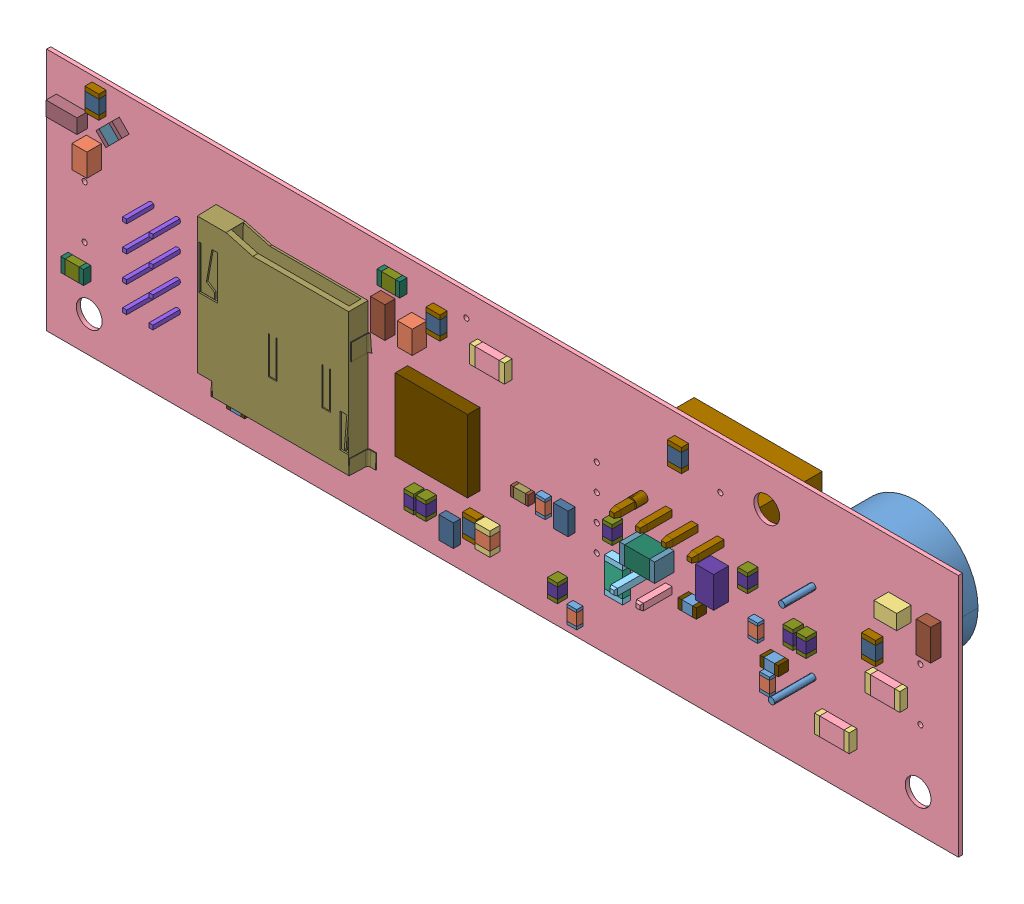
SolidWorks assembly PCB, configuration Default. Lengths in mm.
Overall size (88.26 23.62 14).
270 component instances, 41 part files, 0 mates.
Components (placement in the parent):
- R05-2-1: R05-2 [Default] at origin size (0.95 1.7 0.6)
  - 959206216-2-1: 959206216-2 [Default] at (123.9521 73.9609 0) size (0.95 0.27 0.6)
    - Extruded-62-1: Extruded-62 [Default] at origin size (0.95 0.27 0.6)
  - 959206352-2-1: 959206352-2 [Default] at (123.9521 74.6759 0) size (0.95 1.16 0.6)
    - Extruded-63-1: Extruded-63 [Default] at origin size (0.95 1.16 0.6)
  - 959206216-2-2: 959206216-2 [Default] at (123.9521 75.3909 0) size (0.95 0.27 0.6)
    - Extruded-62-1: Extruded-62 [Default] at origin size (0.95 0.27 0.6)
- R04-2-1: R04-2 [Default] at origin size (0.95 1.7 0.6)
  - 959206216-2-1: 959206216-2 [Default] at (141.478 81.581 0) size (0.95 0.27 0.6)
    - Extruded-62-1: Extruded-62 [Default] at origin size (0.95 0.27 0.6)
  - 959206352-2-1: 959206352-2 [Default] at (141.478 82.296 0) size (0.95 1.16 0.6)
    - Extruded-63-1: Extruded-63 [Default] at origin size (0.95 1.16 0.6)
  - 959206216-2-2: 959206216-2 [Default] at (141.478 83.011 0) size (0.95 0.27 0.6)
    - Extruded-62-1: Extruded-62 [Default] at origin size (0.95 0.27 0.6)
- R03-2-1: R03-2 [Default] at origin size (3.35 1.75 0.75)
  - 959206760-2-1: 959206760-2 [Default] at (147.8506 77.6516 0) size (0.49 1.75 0.75)
    - Extruded-64-1: Extruded-64 [Default] at origin size (0.49 1.75 0.75)
  - 959206896-2-1: 959206896-2 [Default] at (149.2781 77.6516 0) size (2.36 1.75 0.75)
    - Extruded-65-1: Extruded-65 [Default] at origin size (2.36 1.75 0.75)
  - 959206760-2-2: 959206760-2 [Default] at (150.7056 77.6516 0) size (0.49 1.75 0.75)
    - Extruded-64-1: Extruded-64 [Default] at origin size (0.49 1.75 0.75)
- R02-2-1: R02-2 [Default] at origin size (1.75 3.35 0.75)
  - 959207032-2-1: 959207032-2 [Default] at (128.1431 81.3844 0) size (1.75 0.49 0.75)
    - Extruded-66-1: Extruded-66 [Default] at origin size (1.75 0.49 0.75)
  - 959207168-2-1: 959207168-2 [Default] at (128.1431 79.9569 0) size (1.75 2.36 0.75)
    - Extruded-67-1: Extruded-67 [Default] at origin size (1.75 2.36 0.75)
  - 959207032-2-2: 959207032-2 [Default] at (128.1431 78.5294 0) size (1.75 0.49 0.75)
    - Extruded-66-1: Extruded-66 [Default] at origin size (1.75 0.49 0.75)
- R01-2-1: R01-2 [Default] at origin size (3.35 1.75 0.75)
  - 959206760-2-1: 959206760-2 [Default] at (117.3285 91.9479 0) size (0.49 1.75 0.75)
    - Extruded-64-1: Extruded-64 [Default] at origin size (0.49 1.75 0.75)
  - 959206896-2-1: 959206896-2 [Default] at (115.901 91.9479 0) size (2.36 1.75 0.75)
    - Extruded-65-1: Extruded-65 [Default] at origin size (2.36 1.75 0.75)
  - 959206760-2-2: 959206760-2 [Default] at (114.4735 91.9479 0) size (0.49 1.75 0.75)
    - Extruded-64-1: Extruded-64 [Default] at origin size (0.49 1.75 0.75)
- U3-2-1: U3-2 [Default] at origin size (43.25 15.95 5.5)
  - 959206080-2-1: 959206080-2 [Default] at (102.177 84.441 -2.3912) size (43.25 15.95 2)
    - Extruded-68-1: Extruded-68 [Default] at origin size (43.25 15.95 2)
  - 959205944-2-1: 959205944-2 [Default] at (85.217 88.291 -2.8912) size (0.4 0.4 5.5)
    - Extruded-69-1: Extruded-69 [Default] at origin size (0.4 0.4 5.5)
  - 959205944-2-2: 959205944-2 [Default] at (85.217 85.751 -2.8912) size (0.4 0.4 5.5)
    - Extruded-69-1: Extruded-69 [Default] at origin size (0.4 0.4 5.5)
  - 959205944-2-3: 959205944-2 [Default] at (82.677 88.291 -2.8912) size (0.4 0.4 5.5)
    - Extruded-69-1: Extruded-69 [Default] at origin size (0.4 0.4 5.5)
  - 959205944-2-4: 959205944-2 [Default] at (82.677 85.751 -2.8912) size (0.4 0.4 5.5)
    - Extruded-69-1: Extruded-69 [Default] at origin size (0.4 0.4 5.5)
  - 959205944-2-5: 959205944-2 [Default] at (85.217 83.211 -2.8912) size (0.4 0.4 5.5)
    - Extruded-69-1: Extruded-69 [Default] at origin size (0.4 0.4 5.5)
  - 959205944-2-6: 959205944-2 [Default] at (85.217 80.671 -2.8912) size (0.4 0.4 5.5)
    - Extruded-69-1: Extruded-69 [Default] at origin size (0.4 0.4 5.5)
  - 959205944-2-7: 959205944-2 [Default] at (82.677 83.211 -2.8912) size (0.4 0.4 5.5)
    - Extruded-69-1: Extruded-69 [Default] at origin size (0.4 0.4 5.5)
  - 959205944-2-8: 959205944-2 [Default] at (82.677 80.671 -2.8912) size (0.4 0.4 5.5)
    - Extruded-69-1: Extruded-69 [Default] at origin size (0.4 0.4 5.5)
- R11-2-1: R11-2 [Default] at origin size (1.35 2.2 0.7)
  - 959207304-2-1: 959207304-2 [Default] at (133.9849 94.0691 0) size (1.35 0.42 0.7)
    - Extruded-70-1: Extruded-70 [Default] at origin size (1.35 0.42 0.7)
  - 959207440-2-1: 959207440-2 [Default] at (133.9849 93.1791 0) size (1.35 1.36 0.7)
    - Extruded-71-1: Extruded-71 [Default] at origin size (1.35 1.36 0.7)
  - 959207304-2-2: 959207304-2 [Default] at (133.9849 92.2891 0) size (1.35 0.42 0.7)
    - Extruded-70-1: Extruded-70 [Default] at origin size (1.35 0.42 0.7)
- Q3-2-1: Q3-2 [Default] at origin size (1.4 3 1)
  - 959206624-2-1: 959206624-2 [Default] at (105.664 90.805 0.1) size (1.4 3 1)
    - Extruded-72-1: Extruded-72 [Default] at origin size (1.4 3 1)
- P6-2-1: P6-2 [Default] at origin size (16.31 15.21 2.47)
  - User Library-Micro SD-2-1: User Library-Micro SD-2 [Default] at (103.6713 76.9862 0.04) x (-1 0 0) z (0 0 1) size (16.31 15.21 2.47)
- Q1-2-1: Q1-2 [Default] at origin size (3 1.4 1)
  - 959206488-2-1: 959206488-2 [Default] at (75.057 92.3634 0.1) size (3 1.4 1)
    - Extruded-73-1: Extruded-73 [Default] at origin size (3 1.4 1)
- C1-2-1: C1-2 [Default] at origin size (3.4 1.8 1.9)
  - 959208392-2-1: 959208392-2 [Default] at (133.022 83.687 0) size (0.5 1.8 1.9)
    - Extruded-74-1: Extruded-74 [Default] at origin size (0.5 1.8 1.9)
  - 959208392-2-2: 959208392-2 [Default] at (130.122 83.687 0) size (0.5 1.8 1.9)
    - Extruded-74-1: Extruded-74 [Default] at origin size (0.5 1.8 1.9)
  - 959208256-2-1: 959208256-2 [Default] at (131.572 83.687 0) size (2.4 1.8 1.9)
    - Extruded-75-1: Extruded-75 [Default] at origin size (2.4 1.8 1.9)
- C2-2-1: C2-2 [Default] at origin size (0.95 1.75 1)
  - 959208664-2-1: 959208664-2 [Default] at (140.8925 85.698 0) size (0.95 0.35 1)
    - Extruded-76-1: Extruded-76 [Default] at origin size (0.95 0.35 1)
  - 959208664-2-2: 959208664-2 [Default] at (140.8925 87.098 0) size (0.95 0.35 1)
    - Extruded-76-1: Extruded-76 [Default] at origin size (0.95 0.35 1)
  - 959208528-2-1: 959208528-2 [Default] at (140.8925 86.398 0) size (0.95 1.05 1)
    - Extruded-77-1: Extruded-77 [Default] at origin size (0.95 1.05 1)
- C3-2-1: C3-2 [Default] at origin size (0.95 1.75 1)
  - 959208664-2-1: 959208664-2 [Default] at (146.558 83.0961 0) size (0.95 0.35 1)
    - Extruded-76-1: Extruded-76 [Default] at origin size (0.95 0.35 1)
  - 959208664-2-2: 959208664-2 [Default] at (146.558 84.4961 0) size (0.95 0.35 1)
    - Extruded-76-1: Extruded-76 [Default] at origin size (0.95 0.35 1)
  - 959208528-2-1: 959208528-2 [Default] at (146.558 83.7961 0) size (0.95 1.05 1)
    - Extruded-77-1: Extruded-77 [Default] at origin size (0.95 1.05 1)
- C5-2-1: C5-2 [Default] at origin size (1.75 0.95 1)
  - 959208936-2-1: 959208936-2 [Default] at (142.772 80.518 0) size (0.35 0.95 1)
    - Extruded-78-1: Extruded-78 [Default] at origin size (0.35 0.95 1)
  - 959208936-2-2: 959208936-2 [Default] at (144.172 80.518 0) size (0.35 0.95 1)
    - Extruded-78-1: Extruded-78 [Default] at origin size (0.35 0.95 1)
  - 959208800-2-1: 959208800-2 [Default] at (143.472 80.518 0) size (1.05 0.95 1)
    - Extruded-79-1: Extruded-79 [Default] at origin size (1.05 0.95 1)
- C6-2-1: C6-2 [Default] at origin size (1.75 0.95 1)
  - 959208800-2-1: 959208800-2 [Default] at (135.5285 81.379 0) size (1.05 0.95 1)
    - Extruded-79-1: Extruded-79 [Default] at origin size (1.05 0.95 1)
  - 959208936-2-1: 959208936-2 [Default] at (136.2285 81.379 0) size (0.35 0.95 1)
    - Extruded-78-1: Extruded-78 [Default] at origin size (0.35 0.95 1)
  - 959208936-2-2: 959208936-2 [Default] at (134.8286 81.379 0) size (0.35 0.95 1)
    - Extruded-78-1: Extruded-78 [Default] at origin size (0.35 0.95 1)
- C7-2-1: C7-2 [Default] at origin size (0.95 1.75 1)
  - 959208528-2-1: 959208528-2 [Default] at (145.288 83.8282 0) size (0.95 1.05 1)
    - Extruded-77-1: Extruded-77 [Default] at origin size (0.95 1.05 1)
  - 959208664-2-1: 959208664-2 [Default] at (145.288 83.1282 0) size (0.95 0.35 1)
    - Extruded-76-1: Extruded-76 [Default] at origin size (0.95 0.35 1)
  - 959208664-2-2: 959208664-2 [Default] at (145.288 84.5282 0) size (0.95 0.35 1)
    - Extruded-76-1: Extruded-76 [Default] at origin size (0.95 0.35 1)
- C8-2-1: C8-2 [Default] at origin size (1.45 2.2 1)
  - 959207984-2-1: 959207984-2 [Default] at (115.697 77.2073 0) size (1.45 1.2 1)
    - Extruded-80-1: Extruded-80 [Default] at origin size (1.45 1.2 1)
  - 959207848-2-1: 959207848-2 [Default] at (115.697 78.0573 0) size (1.45 0.5 1)
    - Extruded-81-1: Extruded-81 [Default] at origin size (1.45 0.5 1)
  - 959207848-2-2: 959207848-2 [Default] at (115.697 76.3573 0) size (1.45 0.5 1)
    - Extruded-81-1: Extruded-81 [Default] at origin size (1.45 0.5 1)
- C9-2-1: C9-2 [Default] at origin size (0.95 1.75 1)
  - 959208528-2-1: 959208528-2 [Default] at (108.577 76.835 0) size (0.95 1.05 1)
    - Extruded-77-1: Extruded-77 [Default] at origin size (0.95 1.05 1)
  - 959208664-2-1: 959208664-2 [Default] at (108.577 76.135 0) size (0.95 0.35 1)
    - Extruded-76-1: Extruded-76 [Default] at origin size (0.95 0.35 1)
  - 959208664-2-2: 959208664-2 [Default] at (108.577 77.535 0) size (0.95 0.35 1)
    - Extruded-76-1: Extruded-76 [Default] at origin size (0.95 0.35 1)
- C10-2-1: C10-2 [Default] at origin size (0.95 1.75 1)
  - 959208664-2-1: 959208664-2 [Default] at (109.7632 77.5843 0) size (0.95 0.35 1)
    - Extruded-76-1: Extruded-76 [Default] at origin size (0.95 0.35 1)
  - 959208664-2-2: 959208664-2 [Default] at (109.7632 76.1843 0) size (0.95 0.35 1)
    - Extruded-76-1: Extruded-76 [Default] at origin size (0.95 0.35 1)
  - 959208528-2-1: 959208528-2 [Default] at (109.7632 76.8843 0) size (0.95 1.05 1)
    - Extruded-77-1: Extruded-77 [Default] at origin size (0.95 1.05 1)
- C11-2-1: C11-2 [Default] at origin size (0.95 1.75 1)
  - 959208664-2-1: 959208664-2 [Default] at (122.4827 75.652 0) size (0.95 0.35 1)
    - Extruded-76-1: Extruded-76 [Default] at origin size (0.95 0.35 1)
  - 959208664-2-2: 959208664-2 [Default] at (122.4827 77.052 0) size (0.95 0.35 1)
    - Extruded-76-1: Extruded-76 [Default] at origin size (0.95 0.35 1)
  - 959208528-2-1: 959208528-2 [Default] at (122.4827 76.352 0) size (0.95 1.05 1)
    - Extruded-77-1: Extruded-77 [Default] at origin size (0.95 1.05 1)
- C12-2-1: C12-2 [Default] at origin size (1.75 0.95 1)
  - 959208936-2-1: 959208936-2 [Default] at (92.521 76.327 0) size (0.35 0.95 1)
    - Extruded-78-1: Extruded-78 [Default] at origin size (0.35 0.95 1)
  - 959208936-2-2: 959208936-2 [Default] at (91.121 76.327 0) size (0.35 0.95 1)
    - Extruded-78-1: Extruded-78 [Default] at origin size (0.35 0.95 1)
  - 959208800-2-1: 959208800-2 [Default] at (91.821 76.327 0) size (1.05 0.95 1)
    - Extruded-79-1: Extruded-79 [Default] at origin size (1.05 0.95 1)
- P1-2-1: P1-2 [Default] at origin size (7.4 5.75 10.4)
  - P1-subassembly-1-2-1: P1-subassembly-1-2 [Default] at (131.5051 81.6569 -0.3912) x (-1 0 0) z (0 -1 0) size (7.4 10.4 5.75)
    - User Library-JST B2B-XH-A-10-1: User Library-JST B2B-XH-A-10 [Default] at origin size (0.64 3.4 0.64)
    - User Library-JST B2B-XH-A-11-1: User Library-JST B2B-XH-A-11 [Default] at origin size (0.64 3.4 0.64)
    - User Library-JST B2B-XH-A-12-1: User Library-JST B2B-XH-A-12 [Default] at origin size (0.64 4.5 0.64)
    - User Library-JST B2B-XH-A-13-1: User Library-JST B2B-XH-A-13 [Default] at origin size (0.64 4.5 0.64)
    - User Library-JST B2B-XH-A-14-1: User Library-JST B2B-XH-A-14 [Default] at origin size (7.4 7 5.75)
- P3-2-1: P3-2 [Default] at origin size (12.4 5.75 10.4)
  - SW3dPS-jst-b4b-xh-a-1-2-1: SW3dPS-jst-b4b-xh-a-1-2 [Default] at (134.0049 88.1301 -0.3912) x (-1 0 0) z (0 -1 0) size (12.4 10.4 5.75)
- P4-2-1: P4-2 [Default] at origin
  - connector-2-1: connector-2 [Default] at (76.2639 56.9549 -0.3912) x (0 1 0) z (0 0 -1)
- P5-2-1: P5-2 [Default] at origin
  - connector-2-1: connector-2 [Default] at (157.0351 111.9551 -0.3912) x (0 -1 0) z (0 0 -1)
- Q2-2-1: Q2-2 [Default] at origin size (1.4 3 1)
  - 959206624-2-1: 959206624-2 [Default] at (158.496 90.17 0.1) size (1.4 3 1)
    - Extruded-72-1: Extruded-72 [Default] at origin size (1.4 3 1)
- R1-2-1: R1-2 [Default] at origin size (0.95 1.7 0.6)
  - 959206216-2-1: 959206216-2 [Default] at (142.6211 77.6287 0) size (0.95 0.27 0.6)
    - Extruded-62-1: Extruded-62 [Default] at origin size (0.95 0.27 0.6)
  - 959206352-2-1: 959206352-2 [Default] at (142.6211 78.3437 0) size (0.95 1.16 0.6)
    - Extruded-63-1: Extruded-63 [Default] at origin size (0.95 1.16 0.6)
  - 959206216-2-2: 959206216-2 [Default] at (142.6211 79.0587 0) size (0.95 0.27 0.6)
    - Extruded-62-1: Extruded-62 [Default] at origin size (0.95 0.27 0.6)
- R2-2-1: R2-2 [Default] at origin size (1.4 2.15 0.7)
  - 959208120-2-1: 959208120-2 [Default] at (111.8912 75.852 0) size (1.4 2.15 0.7)
    - Extruded-82-1: Extruded-82 [Default] at origin size (1.4 2.15 0.7)
- R3-2-1: R3-2 [Default] at origin size (1.35 2.2 0.7)
  - 959207304-2-1: 959207304-2 [Default] at (114.1729 78.1061 0) size (1.35 0.42 0.7)
    - Extruded-70-1: Extruded-70 [Default] at origin size (1.35 0.42 0.7)
  - 959207440-2-1: 959207440-2 [Default] at (114.1729 77.2161 0) size (1.35 1.36 0.7)
    - Extruded-71-1: Extruded-71 [Default] at origin size (1.35 1.36 0.7)
  - 959207304-2-2: 959207304-2 [Default] at (114.1729 76.3261 0) size (1.35 0.42 0.7)
    - Extruded-70-1: Extruded-70 [Default] at origin size (1.35 0.42 0.7)
- R4-2-1: R4-2 [Default] at origin size (1.7 0.95 0.6)
  - 959209072-2-1: 959209072-2 [Default] at (119.5871 82.2961 0) size (0.27 0.95 0.6)
    - Extruded-83-1: Extruded-83 [Default] at origin size (0.27 0.95 0.6)
  - 959209208-2-1: 959209208-2 [Default] at (118.8721 82.2961 0) size (1.16 0.95 0.6)
    - Extruded-84-1: Extruded-84 [Default] at origin size (1.16 0.95 0.6)
  - 959209072-2-2: 959209072-2 [Default] at (118.1571 82.2961 0) size (0.27 0.95 0.6)
    - Extruded-83-1: Extruded-83 [Default] at origin size (0.27 0.95 0.6)
- R5-2-1: R5-2 [Default] at origin size (0.95 1.7 0.6)
  - 959206216-2-1: 959206216-2 [Default] at (120.9041 81.6699 0) size (0.95 0.27 0.6)
    - Extruded-62-1: Extruded-62 [Default] at origin size (0.95 0.27 0.6)
  - 959206352-2-1: 959206352-2 [Default] at (120.9041 82.3849 0) size (0.95 1.16 0.6)
    - Extruded-63-1: Extruded-63 [Default] at origin size (0.95 1.16 0.6)
  - 959206216-2-2: 959206216-2 [Default] at (120.9041 83.0999 0) size (0.95 0.27 0.6)
    - Extruded-62-1: Extruded-62 [Default] at origin size (0.95 0.27 0.6)
- R6-2-1: R6-2 [Default] at origin size (1.4 2.15 0.7)
  - 959208120-2-1: 959208120-2 [Default] at (122.9827 82.385 0) size (1.4 2.15 0.7)
    - Extruded-82-1: Extruded-82 [Default] at origin size (1.4 2.15 0.7)
- R8-2-1: R8-2 [Default] at origin size (2.51 2.51 0.7)
  - 959207576-2-1: 959207576-2 [Default] at (78.6187 92.1936 0) size (1.25 1.25 0.7)
    - Extruded-85-1: Extruded-85 [Default] at origin size (1.25 1.25 0.7)
  - 959207712-2-1: 959207712-2 [Default] at (79.248 92.8229 0) size (1.92 1.92 0.7)
    - Extruded-86-1: Extruded-86 [Default] at origin size (1.92 1.92 0.7)
  - 959207576-2-2: 959207576-2 [Default] at (79.8773 93.4522 0) size (1.25 1.25 0.7)
    - Extruded-85-1: Extruded-85 [Default] at origin size (1.25 1.25 0.7)
- R13-2-1: R13-2 [Default] at origin size (2.2 1.35 0.7)
  - 959209344-2-1: 959209344-2 [Default] at (105.4089 93.8529 0) size (0.42 1.35 0.7)
    - Extruded-87-1: Extruded-87 [Default] at origin size (0.42 1.35 0.7)
  - 959209480-2-1: 959209480-2 [Default] at (106.2989 93.8529 0) size (1.36 1.35 0.7)
    - Extruded-88-1: Extruded-88 [Default] at origin size (1.36 1.35 0.7)
  - 959209344-2-2: 959209344-2 [Default] at (107.1889 93.8529 0) size (0.42 1.35 0.7)
    - Extruded-87-1: Extruded-87 [Default] at origin size (0.42 1.35 0.7)
- R7-2-1: R7-2 [Default] at origin size (2.2 1.35 0.7)
  - 959209344-2-1: 959209344-2 [Default] at (76.5821 79.5961 0) size (0.42 1.35 0.7)
    - Extruded-87-1: Extruded-87 [Default] at origin size (0.42 1.35 0.7)
  - 959209480-2-1: 959209480-2 [Default] at (75.6921 79.5961 0) size (1.36 1.35 0.7)
    - Extruded-88-1: Extruded-88 [Default] at origin size (1.36 1.35 0.7)
  - 959209344-2-2: 959209344-2 [Default] at (74.8021 79.5961 0) size (0.42 1.35 0.7)
    - Extruded-87-1: Extruded-87 [Default] at origin size (0.42 1.35 0.7)
- R9-2-1: R9-2 [Default] at origin size (1.35 2.2 0.7)
  - 959207304-2-1: 959207304-2 [Default] at (77.5971 95.5049 0) size (1.35 0.42 0.7)
    - Extruded-70-1: Extruded-70 [Default] at origin size (1.35 0.42 0.7)
  - 959207440-2-1: 959207440-2 [Default] at (77.5971 94.6149 0) size (1.35 1.36 0.7)
    - Extruded-71-1: Extruded-71 [Default] at origin size (1.35 1.36 0.7)
  - 959207304-2-2: 959207304-2 [Default] at (77.5971 93.7249 0) size (1.35 0.42 0.7)
    - Extruded-70-1: Extruded-70 [Default] at origin size (1.35 0.42 0.7)
- R14-2-1: R14-2 [Default] at origin size (1.35 2.2 0.7)
  - 959207304-2-1: 959207304-2 [Default] at (110.6132 93.495 0) size (1.35 0.42 0.7)
    - Extruded-70-1: Extruded-70 [Default] at origin size (1.35 0.42 0.7)
  - 959207440-2-1: 959207440-2 [Default] at (110.6132 92.605 0) size (1.35 1.36 0.7)
    - Extruded-71-1: Extruded-71 [Default] at origin size (1.35 1.36 0.7)
  - 959207304-2-2: 959207304-2 [Default] at (110.6132 91.715 0) size (1.35 0.42 0.7)
    - Extruded-70-1: Extruded-70 [Default] at origin size (1.35 0.42 0.7)
- R10-2-1: R10-2 [Default] at origin size (3.35 1.75 0.75)
  - 959206760-2-1: 959206760-2 [Default] at (152.7506 83.5661 0) size (0.49 1.75 0.75)
    - Extruded-64-1: Extruded-64 [Default] at origin size (0.49 1.75 0.75)
  - 959206896-2-1: 959206896-2 [Default] at (154.1781 83.5661 0) size (2.36 1.75 0.75)
    - Extruded-65-1: Extruded-65 [Default] at origin size (2.36 1.75 0.75)
  - 959206760-2-2: 959206760-2 [Default] at (155.6056 83.5661 0) size (0.49 1.75 0.75)
    - Extruded-64-1: Extruded-64 [Default] at origin size (0.49 1.75 0.75)
- R12-2-1: R12-2 [Default] at origin size (1.35 2.2 0.7)
  - 959207304-2-1: 959207304-2 [Default] at (152.7811 87.2879 0) size (1.35 0.42 0.7)
    - Extruded-70-1: Extruded-70 [Default] at origin size (1.35 0.42 0.7)
  - 959207440-2-1: 959207440-2 [Default] at (152.7811 86.3979 0) size (1.35 1.36 0.7)
    - Extruded-71-1: Extruded-71 [Default] at origin size (1.35 1.36 0.7)
  - 959207304-2-2: 959207304-2 [Default] at (152.7811 85.5079 0) size (1.35 0.42 0.7)
    - Extruded-70-1: Extruded-70 [Default] at origin size (1.35 0.42 0.7)
- U1-2-1: U1-2 [Default] at origin size (1.75 3 1.45)
  - 959209616-2-1: 959209616-2 [Default] at (137.668 84.449 0) size (1.75 3 1.45)
    - Extruded-89-1: Extruded-89 [Default] at origin size (1.75 3 1.45)
- U4-2-1: U4-2 [Default] at origin size (7 7 1.2)
  - 959209752-2-1: 959209752-2 [Default] at (110.9632 83.702 0) size (7 7 1.2)
    - Extruded-90-1: Extruded-90 [Default] at origin size (7 7 1.2)
- BUZ1-2-1: BUZ1-2 [Default] at origin size (12 12 14)
  - SW3dPS-WST-1203UX-2-1: SW3dPS-WST-1203UX-2 [Default] at (146.685 84.5049 -0.4912) x (0 -1 0) z (1 0 0) size (12 14 12)
- C4-2-1: C4-2 [Default] at origin size (0.95 1.75 1)
  - 959208528-2-1: 959208528-2 [Default] at (127.791 83.885 0) size (0.95 1.05 1)
    - Extruded-77-1: Extruded-77 [Default] at origin size (0.95 1.05 1)
  - 959208664-2-1: 959208664-2 [Default] at (127.791 83.185 0) size (0.95 0.35 1)
    - Extruded-76-1: Extruded-76 [Default] at origin size (0.95 0.35 1)
  - 959208664-2-2: 959208664-2 [Default] at (127.791 84.585 0) size (0.95 0.35 1)
    - Extruded-76-1: Extruded-76 [Default] at origin size (0.95 0.35 1)
- D1-2-1: D1-2 [Default] at origin size (1.45 2.2 1.4)
  - 959209888-2-1: 959209888-2 [Default] at (77.089 89.876 0) size (1.45 2.2 1.4)
    - Extruded-91-1: Extruded-91 [Default] at origin size (1.45 2.2 1.4)
- D2-2-1: D2-2 [Default] at origin size (2.2 1.45 1.4)
  - 959210024-2-1: 959210024-2 [Default] at (155.107 90.769 0) size (2.2 1.45 1.4)
    - Extruded-92-1: Extruded-92 [Default] at origin size (2.2 1.45 1.4)
- D3-2-1: D3-2 [Default] at origin size (1.45 2.2 1.4)
  - 959209888-2-1: 959209888-2 [Default] at (108.585 90.769 0) size (1.45 2.2 1.4)
    - Extruded-91-1: Extruded-91 [Default] at origin size (1.45 2.2 1.4)
- Board-2-1: Board-2 [Default] at origin size (88.26 23.62 0.39)
